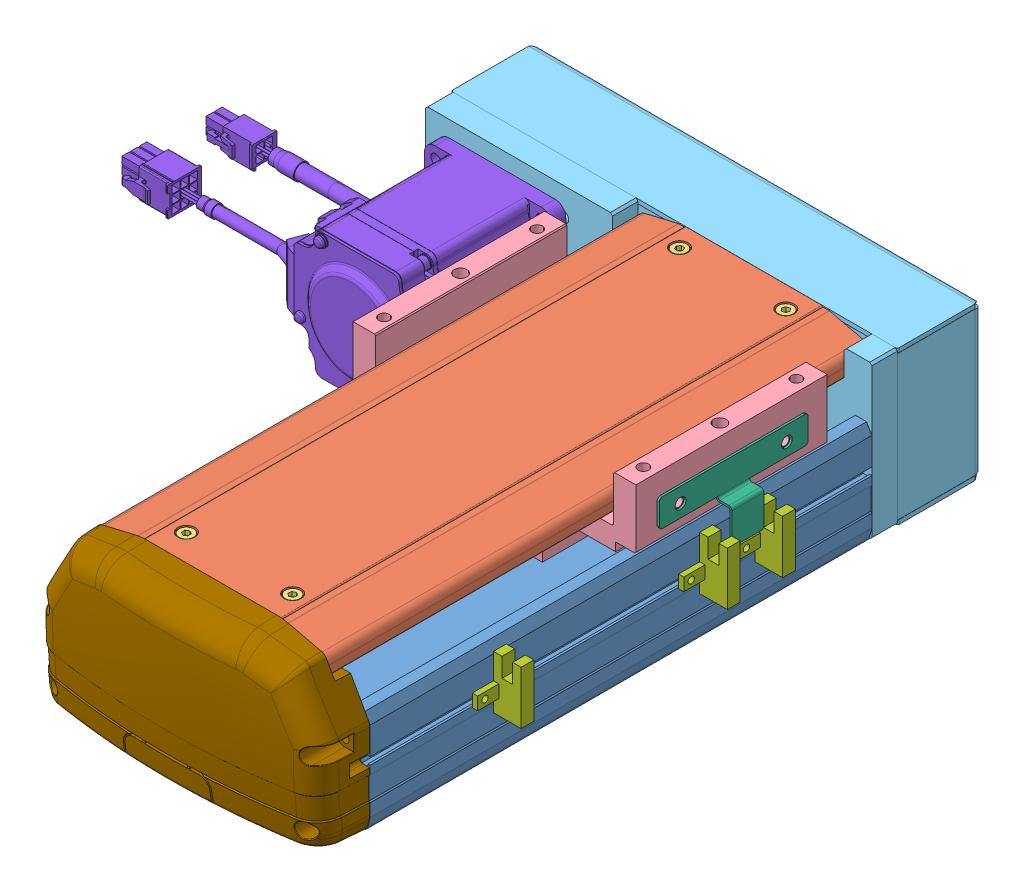
SolidWorks assembly S13-BL-200W, configuration 默认. Lengths in mm.
Overall size (306.2 78 318.96).
14 component instances, 9 part files, 42 mates.
Components (placement in the parent):
- S13-BL底座^S13-BL-200W-1: S13-BL底座^S13-BL-200W [默认] at origin size (135 48 259) (virtual)
- S13-BL上盖^S13-BL-200W-1: S13-BL上盖^S13-BL-200W [默认] at (0 60.45 115.5) size (109 12.5 255) (virtual)
- 内六角圆柱头螺钉M4×8[GB／T70．1-2000]^S13-BL-200W-1: 内六角圆柱头螺钉M4×8[GB／T70．1-2000]^S13-BL-200W [默认] at (-25 72.65 -2) x (0 -1 0) z (-0.993621 0 -0.11277) size (12 7 7) (virtual)
- 内六角圆柱头螺钉M4×8[GB／T70．1-2000]^S13-BL-200W-2: 内六角圆柱头螺钉M4×8[GB／T70．1-2000]^S13-BL-200W [默认] at (25 72.65 -2) x (0 -1 0) z (0.295931 0 -0.955209) size (12 7 7) (virtual)
- 内六角圆柱头螺钉M4×8[GB／T70．1-2000]^S13-BL-200W-3: 内六角圆柱头螺钉M4×8[GB／T70．1-2000]^S13-BL-200W [默认] at (-25 72.65 230) x (0 -1 0) z (0.881053 0 0.473018) size (12 7 7) (virtual)
- 内六角圆柱头螺钉M4×8[GB／T70．1-2000]^S13-BL-200W-4: 内六角圆柱头螺钉M4×8[GB／T70．1-2000]^S13-BL-200W [默认] at (25 72.65 230) x (0 -1 0) z (0.809751 0 0.586773) size (12 7 7) (virtual)
- S13-BC滑座^S13-BL-200W-1: S13-BC滑座^S13-BL-200W [默认] at (1.3936 35.7784 110) x (-1 0 0) z (0 0 -1) size (133 62 90) (virtual)
- 复件 S13-14-BL电机板罩壳^S13-BL-200W-2: 复件 S13-14-BL电机板罩壳^S13-BL-200W [默认] at (34.6396 24.1 343.3649) x (1 0 0) z (0 1 0) size (210.56 52 72) (virtual)
- 复件 外置感应片ST14-17^S13-BL-200W-1: 复件 外置感应片ST14-17^S13-BL-200W [默认] at (67.5 55 65) x (0 0 -1) z (1 0 0) size (70 30.4 7.7) (virtual)
- 复件 光电开关EE-SX672^S13-BL-200W-1: 复件 光电开关EE-SX672^S13-BL-200W [默认] at (67.5 19.7 55) x (0 0 -1) z (1 0 0) size (26 25 13) (virtual)
- 复件 光电开关EE-SX672^S13-BL-200W-2: 复件 光电开关EE-SX672^S13-BL-200W [默认] at (67.5 19.7 81) x (0 0 -1) z (1 0 0) size (26 25 13) (virtual)
- 复件 光电开关EE-SX672^S13-BL-200W-3: 复件 光电开关EE-SX672^S13-BL-200W [默认] at (67.5 19.7 178) x (0 0 -1) z (1 0 0) size (26 25 13) (virtual)
- 复件 松下200W电机MHMF022L1U22^S13-BL-200W-1: 复件 松下200W电机MHMF022L1U22^S13-BL-200W [默认] at (-106.5 35.4 0) x (0 0 -1) z (0 1 0) size (101 149.2 60) (virtual)
- 复件 13-14塑胶端盖 ^S13-BL-200W-1: 复件 13-14塑胶端盖 ^S13-BL-200W [默认] at (0 1 256) x (-1 0 0) z (0 0 -1) size (134.5 73.26 31.04) (virtual)
Mates (geometry in assembly coordinates):
- 重合169: coincident: plane of S13-BL上盖^S13-BL-200W-1 through (-25 68.65 -2) normal (0 1 0); plane of 内六角圆柱头螺钉M4×8[GB／T70．1-2000]^S13-BL-200W-1 through (-25.3947 68.65 1.4777) normal (0 -1 0)
- 同心160: concentric: cylinder of 内六角圆柱头螺钉M4×8[GB／T70．1-2000]^S13-BL-200W-1 through (-25 72.65 -2) axis (0 1 0) radius 3.5; cylinder of S13-BL上盖^S13-BL-200W-1 through (-25 68.65 -2) axis (0 1 0) radius 4
- 同心161: concentric: cylinder of 内六角圆柱头螺钉M4×8[GB／T70．1-2000]^S13-BL-200W-2 through (25 72.65 -2) axis (0 1 0) radius 3.5; cylinder of S13-BL上盖^S13-BL-200W-1 through (25 68.65 -2) axis (0 1 0) radius 4
- 重合171: coincident: plane of S13-BL上盖^S13-BL-200W-1 through (25 68.65 -2) normal (0 1 0); circle of 内六角圆柱头螺钉M4×8[GB／T70．1-2000]^S13-BL-200W-2
- 重合189: coincident: plane of S13-BL上盖^S13-BL-200W-1 through (25 68.65 230) normal (0 1 0); plane of 内六角圆柱头螺钉M4×8[GB／T70．1-2000]^S13-BL-200W-4 through (27.0537 68.65 227.1659) normal (0 -1 0)
- 同心192: concentric: cylinder of S13-BL上盖^S13-BL-200W-1 through (25 68.65 230) axis (0 1 0) radius 4; cylinder of 内六角圆柱头螺钉M4×8[GB／T70．1-2000]^S13-BL-200W-4 through (25 72.65 230) axis (0 1 0) radius 2
- 重合190: coincident: plane of S13-BL上盖^S13-BL-200W-1 through (-25 68.65 230) normal (0 1 0); plane of 内六角圆柱头螺钉M4×8[GB／T70．1-2000]^S13-BL-200W-3 through (-23.3444 68.65 226.9163) normal (0 -1 0)
- 同心193: concentric: cylinder of S13-BL上盖^S13-BL-200W-1 through (-25 68.65 230) axis (0 1 0) radius 4; cylinder of 内六角圆柱头螺钉M4×8[GB／T70．1-2000]^S13-BL-200W-3 through (-25 72.65 230) axis (0 1 0) radius 2
- 距离15: distance = 78 mm: plane of S13-BC滑座^S13-BL-200W-1 through (-66.5 78 110) normal (0 1 0); plane of S13-BL底座^S13-BL-200W-1 through (-65.3076 0 259) normal (0 -1 0)
- 重合205: coincident: plane of S13-BL底座^S13-BL-200W-1 through (0 0 0) normal (1 0 0); plane of S13-BL上盖^S13-BL-200W-1 through (0 60.45 115.5) normal (1 0 0)
- 重合244: coincident: plane of S13-BL底座^S13-BL-200W-1 through (0 0 0) normal (0 0 1); plane of assembly through (0 0 0) normal (0 0 1)
- 重合245: coincident: plane of S13-BL底座^S13-BL-200W-1 through (0 0 0) normal (0 1 0); plane of assembly through (0 0 0) normal (0 1 0)
- 重合246: coincident: plane of S13-BL底座^S13-BL-200W-1 through (0 0 0) normal (1 0 0); plane of assembly through (0 0 0) normal (1 0 0)
- 宽度2: width: plane of S13-BL底座^S13-BL-200W-1 through (67.5 43.6699 259) normal (1 0 0); plane of S13-BL底座^S13-BL-200W-1 through (-67.5 43.6699 259) normal (-1 0 0); plane of S13-BC滑座^S13-BL-200W-1 through (-66.5 16 5.4717) normal (-1 0 0); plane of S13-BC滑座^S13-BL-200W-1 through (66.5 16 17.6249) normal (1 0 0)
- 同心203: concentric: cylinder of S13-BL底座^S13-BL-200W-1 through (62.5 39.5 259) axis (0 0 -1) radius 1.4999; cylinder of 复件 13-14塑胶端盖 ^S13-BL-200W-1 through (62.5 39.5 236) axis (0 0 -1) radius 2.1
- 同心204: concentric: cylinder of S13-BL底座^S13-BL-200W-1 through (-62.5 39.5 259) axis (0 0 -1) radius 1.5; cylinder of 复件 13-14塑胶端盖 ^S13-BL-200W-1 through (-62.5 39.5 236) axis (0 0 -1) radius 2.1
- 重合270: coincident: plane of S13-BL底座^S13-BL-200W-1 through (-73.9407 48 236) normal (0 0 1); plane of 复件 13-14塑胶端盖 ^S13-BL-200W-1 through (0 1 236) normal (0 0 1)
- 重合271: coincident: plane of S13-BL底座^S13-BL-200W-1 through (67.5 43.6699 259) normal (1 0 0); plane of 复件 S13-14-BL电机板罩壳^S13-BL-200W-2 through (67.5 1 -12) normal (1 0 0)
- 距离20: distance = 1 mm: plane of 复件 S13-14-BL电机板罩壳^S13-BL-200W-2 through (67.5 1 -12) normal (0 -1 0); plane of S13-BL底座^S13-BL-200W-1 through (32 0 259) normal (0 -1 0)
- 重合273: coincident: plane of S13-BL底座^S13-BL-200W-1 through (-56.7 26.5 0) normal (0 0 -1); plane of 复件 S13-14-BL电机板罩壳^S13-BL-200W-2 through (-37.5 37 0) normal (0 0 1)
- 重合274: coincident: plane of S13-BC滑座^S13-BL-200W-1 through (66.5 16 17.6249) normal (1 0 0); plane of 复件 外置感应片ST14-17^S13-BL-200W-1 through (66.5 55 65) normal (-1 0 0)
- 同心206: concentric: cylinder of S13-BC滑座^S13-BL-200W-1 through (67 61 44) axis (1 0 0) radius 2.1; cylinder of 复件 外置感应片ST14-17^S13-BL-200W-1 through (67.5 61 44) axis (1 0 0) radius 2.55
- 同心207: concentric: cylinder of S13-BC滑座^S13-BL-200W-1 through (67 61 94) axis (1 0 0) radius 2.1; cylinder of 复件 外置感应片ST14-17^S13-BL-200W-1 through (67.5 61 94) axis (1 0 0) radius 2.55
- 重合275: coincident: plane of S13-BL底座^S13-BL-200W-1 through (67.5 43.6699 259) normal (1 0 0); plane of 复件 光电开关EE-SX672^S13-BL-200W-1 through (67.5 44.7 55) normal (-1 0 0)
- 距离22: distance = 19.7 mm: plane of 复件 光电开关EE-SX672^S13-BL-200W-1 through (80.5 19.7 55) normal (0 -1 0); plane of S13-BL底座^S13-BL-200W-1 through (32 0 259) normal (0 -1 0)
- 距离23: distance = 53 mm: plane of 复件 光电开关EE-SX672^S13-BL-200W-1 through (80.5 19.7 49) normal (0 0 -1); plane of S13-BL底座^S13-BL-200W-1 through (-56.7 26.5 0) normal (0 0 -1)
- 重合278: coincident: plane of 复件 光电开关EE-SX672^S13-BL-200W-1 through (80.5 44.7 55) normal (1 0 0); plane of 复件 光电开关EE-SX672^S13-BL-200W-2 through (80.5 44.7 81) normal (1 0 0)
- 重合279: coincident: plane of 复件 光电开关EE-SX672^S13-BL-200W-1 through (70 32.7 65) normal (0 0 1); plane of 复件 光电开关EE-SX672^S13-BL-200W-2 through (70 32.7 65) normal (0 0 -1)
- 重合280: coincident: plane of 复件 光电开关EE-SX672^S13-BL-200W-1 through (80.5 19.7 55) normal (0 -1 0); plane of 复件 光电开关EE-SX672^S13-BL-200W-2 through (80.5 19.7 81) normal (0 -1 0)
- 宽度3: width: plane of 复件 光电开关EE-SX672^S13-BL-200W-1 through (80.5 19.7 59) normal (0 0 1); plane of 复件 光电开关EE-SX672^S13-BL-200W-2 through (80.5 19.7 79) normal (0 0 -1); plane of 复件 外置感应片ST14-17^S13-BL-200W-1 through (74.2 37.6 76.5) normal (0 0 1); plane of 复件 外置感应片ST14-17^S13-BL-200W-1 through (74.2 53 61.5) normal (0 0 -1)
- 重合284: coincident: plane of 复件 光电开关EE-SX672^S13-BL-200W-2 through (80.5 44.7 81) normal (1 0 0); plane of 复件 光电开关EE-SX672^S13-BL-200W-3 through (80.5 44.7 178) normal (1 0 0)
- 重合285: coincident: plane of 复件 光电开关EE-SX672^S13-BL-200W-2 through (80.5 19.7 81) normal (0 -1 0); plane of 复件 光电开关EE-SX672^S13-BL-200W-3 through (80.5 19.7 178) normal (0 -1 0)
- 距离25: distance = 58 mm: plane of 复件 光电开关EE-SX672^S13-BL-200W-3 through (80.5 19.7 178) normal (0 0 1); plane of S13-BL底座^S13-BL-200W-1 through (73.9407 48 236) normal (0 0 1)
- 重合287: coincident: plane of S13-BL上盖^S13-BL-200W-1 through (-54 60.45 243) normal (0 -1 0); plane of 复件 S13-14-BL电机板罩壳^S13-BL-200W-2 through (-30 60.45 0) normal (0 1 0)
- 重合288: coincident: plane of S13-BL上盖^S13-BL-200W-1 through (50.5 64.7864 -12) normal (0 0 -1); plane of 复件 S13-14-BL电机板罩壳^S13-BL-200W-2 through (-139 73 -12) normal (0 0 1)
- 宽度5: width: plane of 复件 S13-14-BL电机板罩壳^S13-BL-200W-2 through (-103.5 10.4 0) normal (0 1 0); plane of 复件 S13-14-BL电机板罩壳^S13-BL-200W-2 through (-103.5 60.4 0) normal (0 -1 0); cylinder of 复件 松下200W电机MHMF022L1U22^S13-BL-200W-1 through (-106.5 35.4 -30) axis (0 0 1) radius 5.5
- 重合289: coincident: plane of 复件 S13-14-BL电机板罩壳^S13-BL-200W-2 through (-37.5 37 0) normal (0 0 1); plane of 复件 松下200W电机MHMF022L1U22^S13-BL-200W-1 through (-131.5 60.4 0) normal (0 0 -1)
- 距离26: distance = 30 mm: moEndPointRef_w of 复件 S13-14-BL电机板罩壳^S13-BL-200W-2; plane of 复件 松下200W电机MHMF022L1U22^S13-BL-200W-1 through (-136.5 10.4 54.5) normal (-1 0 0)
- 距离28: distance = 117 mm: cylinder of S13-BC滑座^S13-BL-200W-1 through (61 78 65) axis (0 1 0) radius 3; plane of 复件 S13-14-BL电机板罩壳^S13-BL-200W-2 through (-37.5 37 -52) normal (0 0 -1)
- 同心208: concentric: cylinder of S13-BC滑座^S13-BL-200W-1 through (67 61 90) axis (1 0 0) radius 2.1; cylinder of 复件 外置感应片ST14-17^S13-BL-200W-1 through (67.5 61 90) axis (1 0 0) radius 2.55
- 同心209: concentric: cylinder of S13-BC滑座^S13-BL-200W-1 through (67 61 40) axis (1 0 0) radius 2.1; cylinder of 复件 外置感应片ST14-17^S13-BL-200W-1 through (67.5 61 40) axis (1 0 0) radius 2.55
- 宽度6: width: plane of 复件 光电开关EE-SX672^S13-BL-200W-2 through (80.5 19.7 75) normal (0 0 -1); plane of 复件 光电开关EE-SX672^S13-BL-200W-1 through (80.5 19.7 55) normal (0 0 1); plane of 复件 外置感应片ST14-17^S13-BL-200W-1 through (74.2 53 57.5) normal (0 0 -1); plane of 复件 外置感应片ST14-17^S13-BL-200W-1 through (74.2 37.6 72.5) normal (0 0 1)
